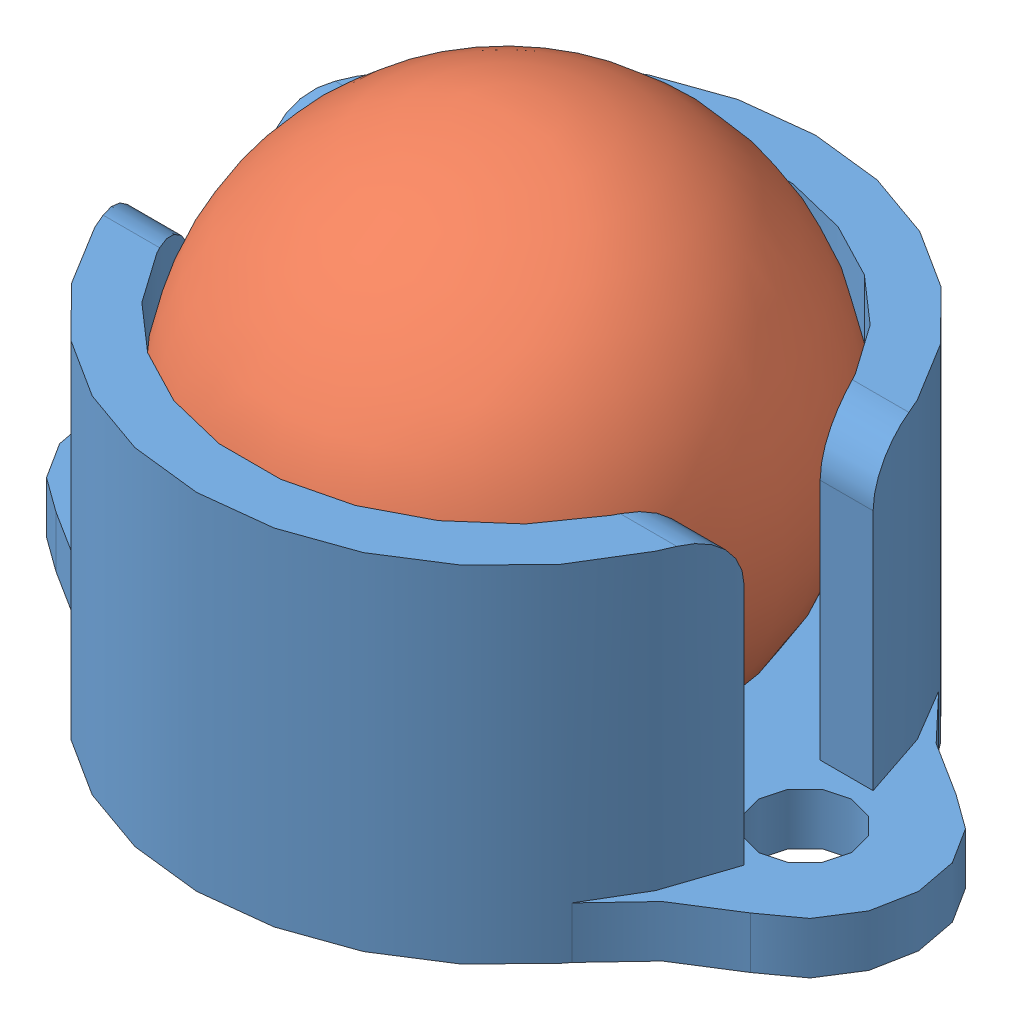
SolidWorks assembly 0.5in Pololu Ball Caster, configuration Default. Lengths in mm.
Overall size (20.32 12.79 15.24).
2 component instances, 2 part files, 0 mates.
Components (placement in the parent):
- 0.5 Caster Housing-1: 0.5 Caster Housing [Default] at (7.6054 5.6787 16.0423) size (20.32 8.51 15.24)
- 0.5 Caster Ball-1: 0.5 Caster Ball [Default] at (7.6054 5.7715 16.0423) size (12.7 12.7 12.7)
